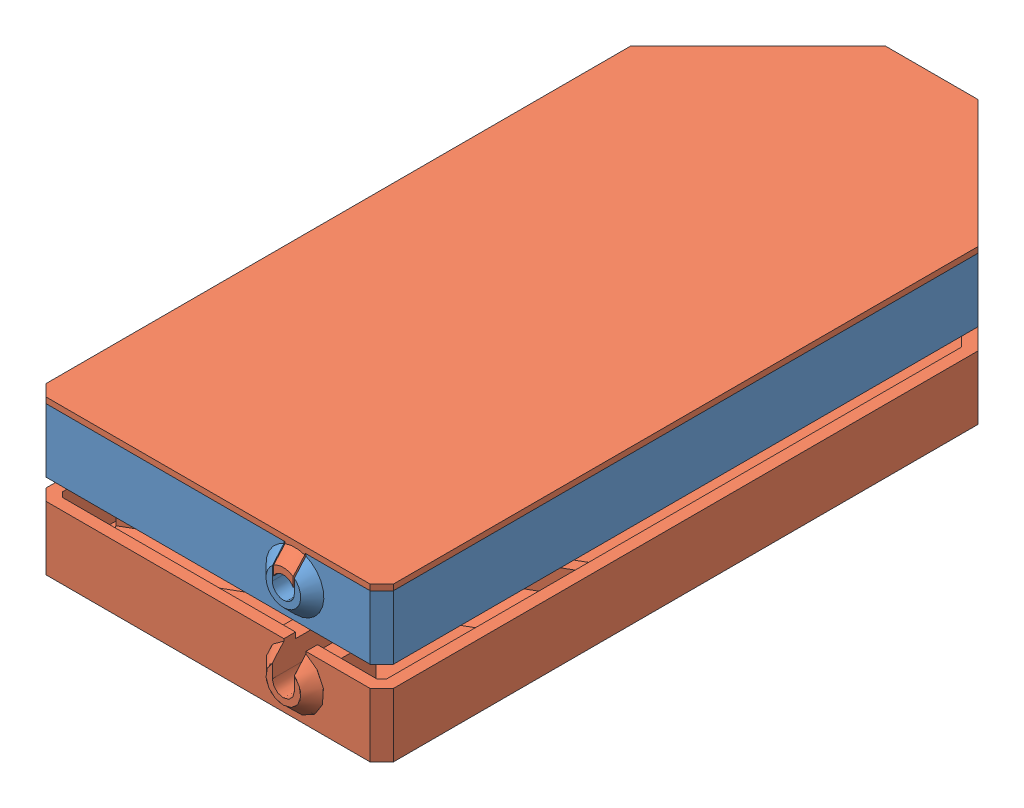
SolidWorks assembly 3DFiberSpectrometer, configuration Default. Lengths in mm.
Overall size (64.67 15 215.22).
2 component instances, 2 part files, 3 mates.
Components (placement in the parent):
- FiberSpecBaseClip-1: FiberSpecBaseClip [Default] at (74.3966 94.4475 164.002) size (64.67 15 215.22)
- FiberSpecLid-1: FiberSpecLid [Default] at (132.1331 106.4475 115.4529) size (60 26.62 127)
Mates (geometry in assembly coordinates):
- Coincident1: coincident aligned: plane of FiberSpecBaseClip-1 through (46.3966 105.4475 201.002) normal (0 0 1); plane of FiberSpecLid-1 through (91.2966 105.4475 201.002) normal (0 0 1)
- Coincident2: coincident aligned: plane of FiberSpecBaseClip-1 through (104.3966 105.4475 98.002) normal (1 0 0); plane of FiberSpecLid-1 through (104.3966 105.4475 199.002) normal (1 0 0)
- Coincident3: coincident anti-aligned: plane of FiberSpecBaseClip-1 through (74.3966 105.4475 164.002) normal (0 1 0); plane of FiberSpecLid-1 through (132.1331 105.4475 115.4529) normal (0 -1 0)
